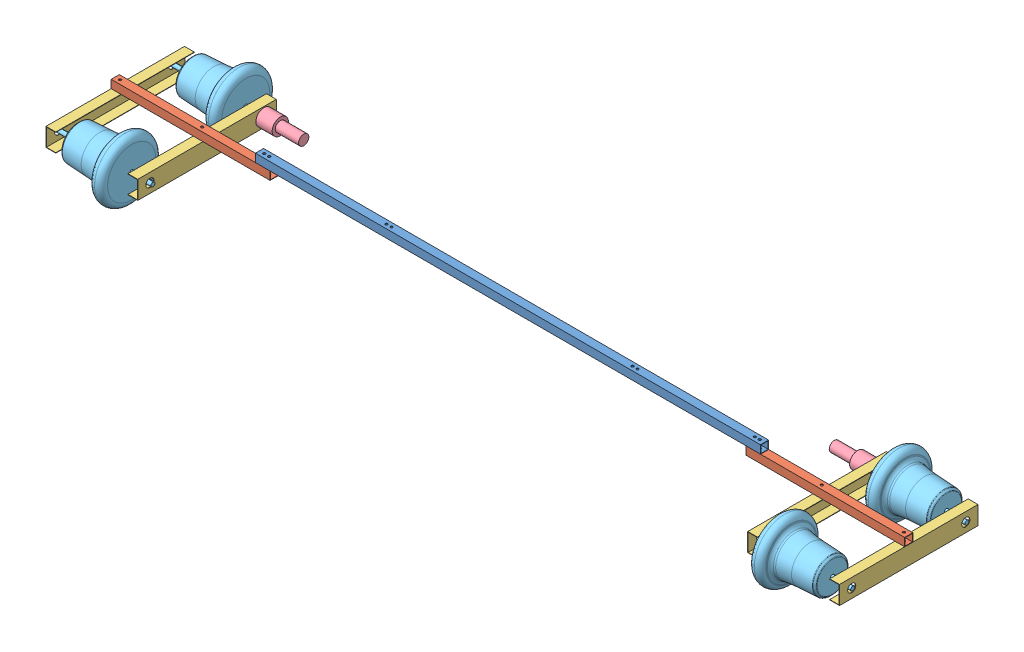
SolidWorks assembly Aribot Assembly File - Hardware Mark 1, configuration Default. Lengths in mm.
Overall size (1952.96 206.65 459.41).
13 component instances, 5 part files, 27 mates.
Components (placement in the parent):
- Main Rod-1: Main Rod [Default] at (303.0132 651.9436 1032.8637) size (1240 20 20)
- Auxiliary Rod-1: Auxiliary Rod [Default] at (-50.9868 631.9436 1032.8637) size (390 20 20)
- Auxiliary Rod-2: Auxiliary Rod [Default] at (1897.0132 631.9436 1032.8637) x (-1 0 0) z (0 0 -1) size (390 20 20)
- Side Unit Main Structural Member-1: Side Unit Main Structural Member [Default] at (-50.9868 621.9436 862.8637) size (24 45 340)
- Side Unit Main Structural Member-2: Side Unit Main Structural Member [Default] at (1671.7632 621.9436 862.8637) size (24 45 340)
- Side Unit Main Structural Member-3: Side Unit Main Structural Member [Default] at (174.2632 621.9436 1202.8637) x (-1 0 0) z (0 0 -1) size (24 45 340)
- Side Unit Main Structural Member-4: Side Unit Main Structural Member [Default] at (1897.0132 621.9436 1202.8637) x (-1 0 0) z (0 0 -1) size (24 45 340)
- Motor Cylinder-2: Motor Cylinder [Default] at (174.2632 599.4436 892.8637) x (0 -0.195761 -0.980652) z (1 0 0) size (40 40 97.5)
- Motor Cylinder-3: Motor Cylinder [Default] at (1671.7632 599.4436 892.8637) x (0 0.847365 0.531011) z (-1 0 0) size (40 40 97.5)
- Wheel-1: Wheel [Default] at (129.2632 475.7586 874.7794) x (1 0 0) z (0 -0.144675 0.989479) size (235 150 150)
- Wheel-2: Wheel [Default] at (129.2632 474.4436 1172.8637) size (235 150 150)
- Wheel-3: Wheel [Default] at (1716.7632 474.4567 1171.0501) x (-1 0 0) z (0 0.014509 -0.999895) size (235 150 150)
- Wheel-4: Wheel [Default] at (1716.7632 493.3775 959.0074) x (-1 0 0) z (0 -0.529149 -0.848529) size (235 150 150)
Mates (geometry in assembly coordinates):
- Coincident1: coincident aligned: circle of Main Rod-1; circle of Auxiliary Rod-2
- Coincident2: coincident aligned: circle of Main Rod-1; circle of Auxiliary Rod-1
- Coincident3: coincident aligned: circle of Auxiliary Rod-1; circle of Side Unit Main Structural Member-1
- Coincident4: coincident aligned: circle of Auxiliary Rod-1; circle of Side Unit Main Structural Member-3
- Coincident5: coincident aligned: circle of Auxiliary Rod-2; circle of Side Unit Main Structural Member-2
- Coincident6: coincident aligned: circle of Auxiliary Rod-2; circle of Side Unit Main Structural Member-4
- Concentric1: concentric anti-aligned: cylinder of Side Unit Main Structural Member-3; cylinder of Motor Cylinder-1 through (283.0633 599.4436 892.8637) axis (-1 0 0) radius 30
- Concentric2: concentric anti-aligned: circle of Side Unit Main Structural Member-3; cylinder of Motor Cylinder-2 through (214.2632 599.4436 892.8637) axis (-1 0 0) radius 20
- Coincident7: coincident anti-aligned: plane of Side Unit Main Structural Member-3 through (174.2632 621.9436 862.8637) normal (1 0 0); plane of Motor Cylinder-2 through (174.2632 599.4436 892.8637) normal (-1 0 0)
- Concentric3: concentric aligned: circle of Side Unit Main Structural Member-2; circle of Motor Cylinder-3
- Coincident8: coincident anti-aligned: plane of Side Unit Main Structural Member-2 through (1671.7632 621.9436 1202.8637) normal (-1 0 0); plane of Motor Cylinder-3 through (1671.7632 599.4436 892.8637) normal (1 0 0)
- Parallel1: parallel anti-aligned: plane of Side Unit Main Structural Member-2 through (1672.7632 620.9436 1202.8637) normal (1 0 0); plane of Side Unit Main Structural Member-4 through (1896.0132 620.9436 862.8637) normal (-1 0 0)
- Parallel4: parallel anti-aligned: plane of Side Unit Main Structural Member-2 through (1672.7632 620.9436 1202.8637) normal (1 0 0); plane of Side Unit Main Structural Member-4 through (1896.0132 620.9436 862.8637) normal (-1 0 0)
- Parallel5: parallel aligned: plane of Main Rod-1 through (1543.0132 641.9436 1042.8637) normal (0 0 1); plane of Auxiliary Rod-2 through (1507.0132 621.9436 1042.8637) normal (0 0 1)
- Coincident9: coincident aligned: plane of Main Rod-1 through (1543.0132 641.9436 1042.8637) normal (0 0 1); plane of Auxiliary Rod-1 through (339.0132 621.9436 1042.8637) normal (0 0 1)
- Perpendicular1: perpendicular: plane of Auxiliary Rod-1 through (339.0132 621.9436 1042.8637) normal (0 0 1); plane of Side Unit Main Structural Member-3 through (174.2632 621.9436 862.8637) normal (1 0 0)
- Perpendicular2: perpendicular: plane of Auxiliary Rod-2 through (1507.0132 621.9436 1042.8637) normal (0 0 1); plane of Side Unit Main Structural Member-2 through (1671.7632 621.9436 1202.8637) normal (-1 0 0)
- Concentric4: concentric anti-aligned: cylinder of Side Unit Main Structural Member-3 through (-165.7368 599.4436 892.8637) axis (1 0 0) radius 10; cylinder of Wheel-1 through (184.2242 599.4436 892.8637) axis (-1 0 0) radius 5
- Parallel8: parallel aligned: plane of Wheel-1 through (-50.7758 599.4436 892.8637) normal (-1 0 0); plane of Wheel-2 through (-50.7758 599.4436 1172.8637) normal (-1 0 0)
- Concentric7: concentric aligned: circle of Side Unit Main Structural Member-1; circle of Wheel-2
- Coincident16: coincident aligned: plane of Wheel-1 through (-50.7758 599.4436 892.8637) normal (-1 0 0); plane of Wheel-2 through (-50.7758 599.4436 1172.8637) normal (-1 0 0)
- Parallel9: parallel aligned: plane of Wheel-3 through (1899.9013 599.4436 1172.8637) normal (1 0 0); plane of Wheel-4 through (1899.9013 599.4436 892.8637) normal (1 0 0)
- Coincident18: coincident aligned: plane of Wheel-3 through (1849.9013 474.4567 1171.0501) normal (1 0 0); plane of Wheel-4 through (1849.9013 493.3775 959.0074) normal (1 0 0)
- Concentric8: concentric anti-aligned: circle of Side Unit Main Structural Member-2; circle of Wheel-4
- Concentric9: concentric anti-aligned: circle of Side Unit Main Structural Member-2; circle of Wheel-3
- Distance1: distance = 45 mm aligned: plane of Wheel-3 through (1716.7632 474.4567 1171.0501) normal (-1 0 0); plane of Side Unit Main Structural Member-2 through (1671.7632 621.9436 1202.8637) normal (-1 0 0)
- Distance2: distance = 45 mm aligned: plane of Side Unit Main Structural Member-3 through (174.2632 621.9436 862.8637) normal (1 0 0); plane of Wheel-2 through (129.2632 474.4436 1172.8637) normal (1 0 0)
